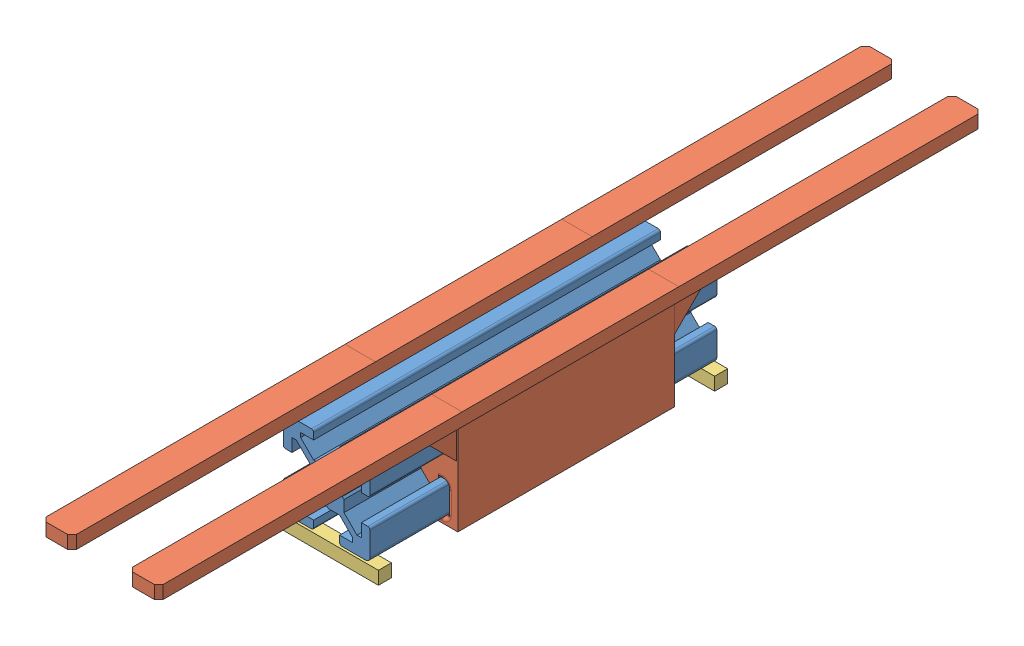
SolidWorks assembly Assieme1, configuration Default. Lengths in mm.
Overall size (27 26 190).
4 component instances, 3 part files, 7 mates.
Components (placement in the parent):
- Profilato serie 5 20x20-1: Profilato serie 5 20x20 [Default] at (35.5314 49.2557 13.7774) size (20 20 80)
- forche-1: forche [Default] at (39.5314 49.2557 16.0184) size (27 24.5 190)
- piedini-10: piedini [Default] at (48.0314 39.2557 13.7774) x (0 0 1) z (-1 0 0) size (3 3 25)
- piedini-11: piedini [Default] at (23.0314 39.2557 94.334) x (0 0 -1) z (1 0 0) size (3 3 25)
Mates (geometry in assembly coordinates):
- Coincidente1: coincident anti-aligned: plane of Profilato serie 5 20x20-1 through (39.5314 49.6557 93.7774) normal (1 0 0); plane of forche-1 through (39.5314 49.2557 86.0184) normal (-1 0 0)
- Coincidente2: coincident anti-aligned: plane of Profilato serie 5 20x20-1 through (32.0314 39.2557 93.7774) normal (0 -1 0); plane of forche-1 through (49.0334 39.2557 76.0184) normal (0 1 0)
- Coincidente6: coincident anti-aligned: plane of Profilato serie 5 20x20-1 through (39.0314 39.2557 93.7774) normal (0 -1 0); plane of piedini-10 through (20.5314 39.2557 13.7774) normal (0 1 0)
- Distanza1: distance = 2.5 mm aligned: plane of Profilato serie 5 20x20-1 through (45.5314 45.7557 93.7774) normal (1 0 0); plane of piedini-10 through (48.0314 39.2557 13.7774) normal (1 0 0)
- Coincidente8: coincident: line of Profilato serie 5 20x20-1 through (39.0314 39.2557 13.7774) axis (1 0 0); plane of piedini-10 through (20.5314 39.2557 13.7774) normal (0 0 -1)
- Coincidente9: coincident: plane of Profilato serie 5 20x20-1 through (32.0314 39.2557 93.7774) normal (0 -1 0); plane of piedini-11 through (49.6912 39.2557 94.334) normal (0 1 0)
- Distanza2: distance = 2.5 mm aligned: plane of Profilato serie 5 20x20-1 through (25.5314 45.7557 93.7774) normal (-1 0 0); plane of piedini-11 through (23.0314 39.2557 94.334) normal (-1 0 0)
